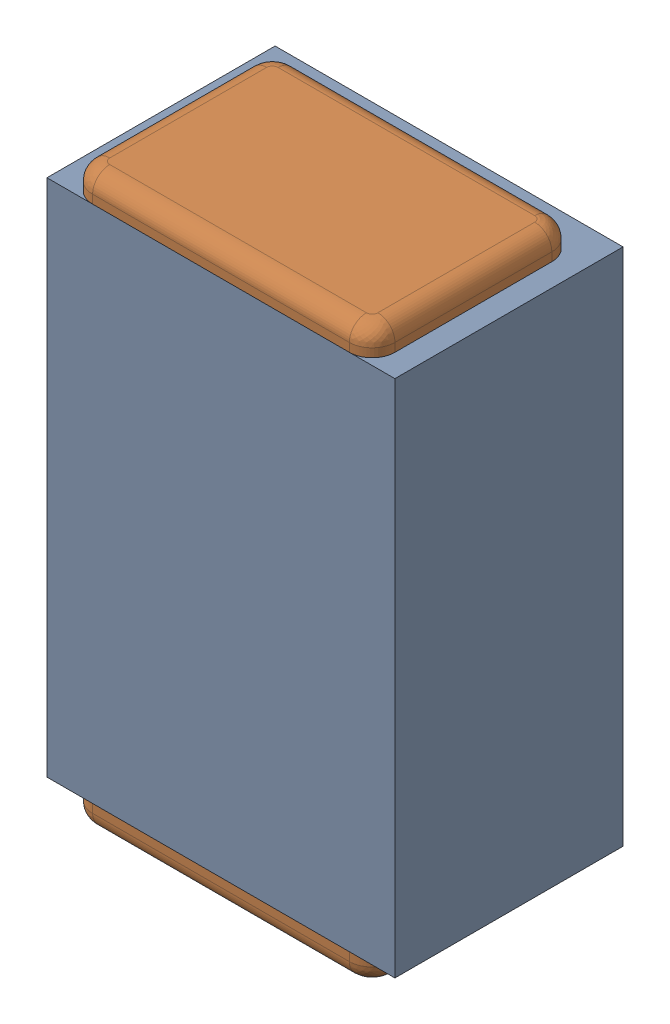
SolidWorks assembly C32, configuration Default. Lengths in mm.
Overall size (0.61 1 0.4).
3 component instances, 2 part files, 0 mates.
Components (placement in the parent):
- 1088881848-1: 1088881848 [Default] at (7.525 31.775 -2.044) size (0.61 0.91 0.4)
  - Extruded-1-1: Extruded-1 [Default] at origin size (0.61 0.91 0.4)
- C0402-1: C0402 [Default] at (7.5251 31.7751 -1.644) x (0 1 0) z (-1 0 0) size (1 0.36 0.54)
